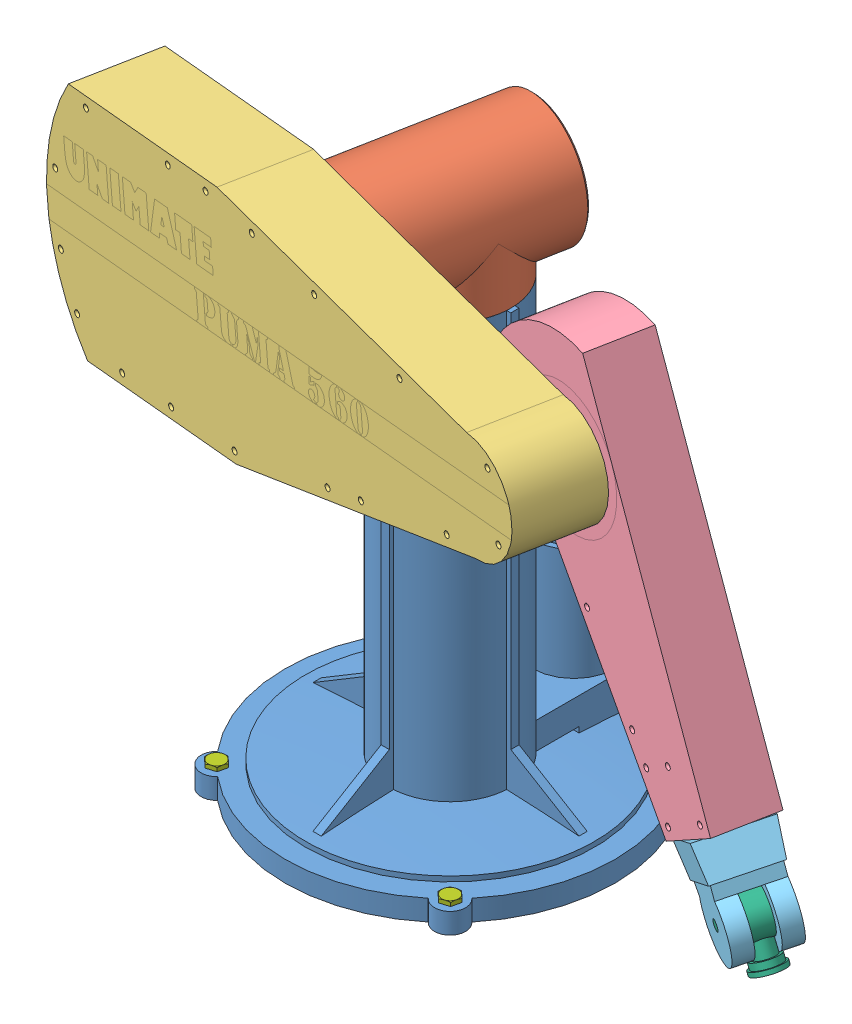
SolidWorks assembly Robot PUMA 560, configuration Predeterminado. Lengths in mm.
Overall size (978.87 823.06 588.52).
12 component instances, 7 part files, 28 mates.
Components (placement in the parent):
- Pieza 1-1: Pieza 1 [Predeterminado] at (-126.1783 -230.6003 0) size (406.4 548.64 431.8)
- Pieza 2-1: Pieza 2 [Predeterminado] at (-126.1783 392.9697 0) x (0.188196 0 -0.982132) z (-0.982132 0 -0.188196) size (238.76 162.56 162.56)
- Pieza 3-1: Pieza 3 [Predeterminado] at (-157.7274 392.9697 164.6445) x (0.188196 0 -0.982132) z (0.976511 0.106834 0.187119) size (127.34 279.4 723.9)
- Pieza 4-1: Pieza 4 [Predeterminado] at (278.2704 439.1008 170.6039) x (-0.188196 0 0.982132) z (-0.831724 -0.531823 -0.159375) size (76.2 478.79 172.27)
- Pieza 5-1: Pieza 5 [Predeterminado] at (465.4606 123.9773 245.2663) x (-0.738009 -0.507717 -0.444484) z (0.42723 0.158298 -0.890178) size (79.32 119.96 81.28)
- Pieza 6-1: Pieza 6 [Predeterminado] at (496.7887 73.1839 251.2694) x (-0.42723 -0.158298 0.890178) z (0.457558 -0.887025 0.061862) size (68.58 50.8 78.74)
- Pieza 7-4: Pieza 7 [Predeterminado] at (-245.7264 -205.2003 -164.3122) x (-0.861479 0 -0.507794) z (0.507794 0 -0.861479) size (20.32 17.78 23.46)
- Pieza 7-5: Pieza 7 [Predeterminado] at (-269.8624 -205.2003 -143.6841) x (-0.292258 0 -0.95634) z (0.95634 0 -0.292258) size (20.32 17.78 23.46)
- Pieza 7-6: Pieza 7 [Predeterminado] at (-269.8624 -205.2003 143.6841) x (-0.292258 0 -0.95634) z (0.95634 0 -0.292258) size (20.32 17.78 23.46)
- Pieza 7-7: Pieza 7 [Predeterminado] at (17.5058 -205.2003 143.6841) x (-0.292258 0 -0.95634) z (0.95634 0 -0.292258) size (20.32 17.78 23.46)
- Pieza 7-8: Pieza 7 [Predeterminado] at (17.5058 -205.2003 -143.6841) x (-0.292258 0 -0.95634) z (0.95634 0 -0.292258) size (20.32 17.78 23.46)
- Pieza 7-9: Pieza 7 [Predeterminado] at (-6.6302 -205.2003 -164.3122) x (-0.292258 0 -0.95634) z (0.95634 0 -0.292258) size (20.32 17.78 23.46)
Mates (geometry in assembly coordinates):
- Coincidente1: coincident: plane of Pieza 1-1 through (-126.1783 318.0397 0) normal (0 1 0); plane of Pieza 2-1 through (-126.1783 318.0397 0) normal (0 -1 0)
- Coincidente2: coincident: circle of Pieza 1-1; circle of Pieza 2-1
- Coincidente3: coincident: plane of Pieza 2-1; plane of Pieza 3-1
- Concéntrica1: concentric: circle of Pieza 2-1; circle of Pieza 3-1
- Coincidente4: coincident: plane of Pieza 3-1; plane of Pieza 4-1
- Concéntrica2: concentric: circle of Pieza 3-1; circle of Pieza 4-1
- Coincidente5: coincident: plane of Pieza 4-1; plane of Pieza 5-1
- Coincidente6: coincident: circle of Pieza 4-1; circle of Pieza 5-1
- Concéntrica3: concentric: cylinder of Pieza 5-1 through (471.8543 66.7662 304.8269) axis (0.4347 0.146152 -0.888637) radius 6.35; cylinder of Pieza 6-1 through (474.6147 67.6943 299.1841) axis (0.4347 0.146152 -0.888637) radius 6.35
- Coincidente7: coincident: plane of Pieza 5-1; plane of Pieza 6-1
- Concéntrica6: concentric: cylinder of Pieza 1-1 through (-245.7264 -230.6003 -164.3122) axis (0 1 0) radius 6.35; cylinder of Pieza 7-4 through (-245.7264 -217.9003 -164.3122) axis (0 1 0) radius 6.35
- Coincidente10: coincident: plane of Pieza 1-1 through (-126.1783 -205.2003 0) normal (0 1 0); plane of Pieza 7-4 through (-245.7264 -205.2003 -164.3122) normal (0 -1 0)
- Concéntrica7: concentric: cylinder of Pieza 1-1 through (-269.8624 -230.6003 -143.6841) axis (0 1 0) radius 6.35; cylinder of Pieza 7-5 through (-269.8624 -217.9003 -143.6841) axis (0 1 0) radius 6.35
- Coincidente11: coincident: plane of Pieza 1-1 through (-126.1783 -205.2003 0) normal (0 1 0); plane of Pieza 7-5 through (-269.8624 -205.2003 -143.6841) normal (0 -1 0)
- Bloquear2: lock: unknown of Pieza 1-1; unknown of Pieza 7-4
- Bloquear3: lock: unknown of Pieza 1-1; unknown of Pieza 7-5
- Concéntrica10: concentric: cylinder of Pieza 1-1 through (-269.8624 -230.6003 143.6841) axis (0 1 0) radius 6.35; cylinder of Pieza 7-6 through (-269.8624 -217.9003 143.6841) axis (0 1 0) radius 6.35
- Coincidente12: coincident: plane of Pieza 1-1 through (-126.1783 -205.2003 0) normal (0 1 0); plane of Pieza 7-6 through (-269.8624 -205.2003 143.6841) normal (0 -1 0)
- Bloquear4: lock: unknown of Pieza 1-1; unknown of Pieza 7-6
- Concéntrica11: concentric: cylinder of Pieza 1-1 through (17.5058 -230.6003 143.6841) axis (0 1 0) radius 6.35; cylinder of Pieza 7-7 through (17.5058 -217.9003 143.6841) axis (0 1 0) radius 6.35
- Coincidente13: coincident: plane of Pieza 1-1 through (-126.1783 -205.2003 0) normal (0 1 0); plane of Pieza 7-7 through (17.5058 -205.2003 143.6841) normal (0 -1 0)
- Bloquear5: lock: unknown of Pieza 1-1; unknown of Pieza 7-7
- Concéntrica12: concentric: cylinder of Pieza 1-1 through (17.5058 -230.6003 -143.6841) axis (0 1 0) radius 6.35; cylinder of Pieza 7-8 through (17.5058 -217.9003 -143.6841) axis (0 1 0) radius 6.35
- Coincidente14: coincident: plane of Pieza 1-1 through (-126.1783 -205.2003 0) normal (0 1 0); plane of Pieza 7-8 through (17.5058 -205.2003 -143.6841) normal (0 -1 0)
- Bloquear6: lock: unknown of Pieza 1-1; unknown of Pieza 7-8
- Concéntrica13: concentric: cylinder of Pieza 1-1 through (-6.6302 -230.6003 -164.3122) axis (0 1 0) radius 6.35; cylinder of Pieza 7-9 through (-6.6302 -217.9003 -164.3122) axis (0 1 0) radius 6.35
- Coincidente15: coincident: plane of Pieza 1-1 through (-126.1783 -205.2003 0) normal (0 1 0); plane of Pieza 7-9 through (-6.6302 -205.2003 -164.3122) normal (0 -1 0)
- Bloquear7: lock: unknown of Pieza 1-1; unknown of Pieza 7-9
